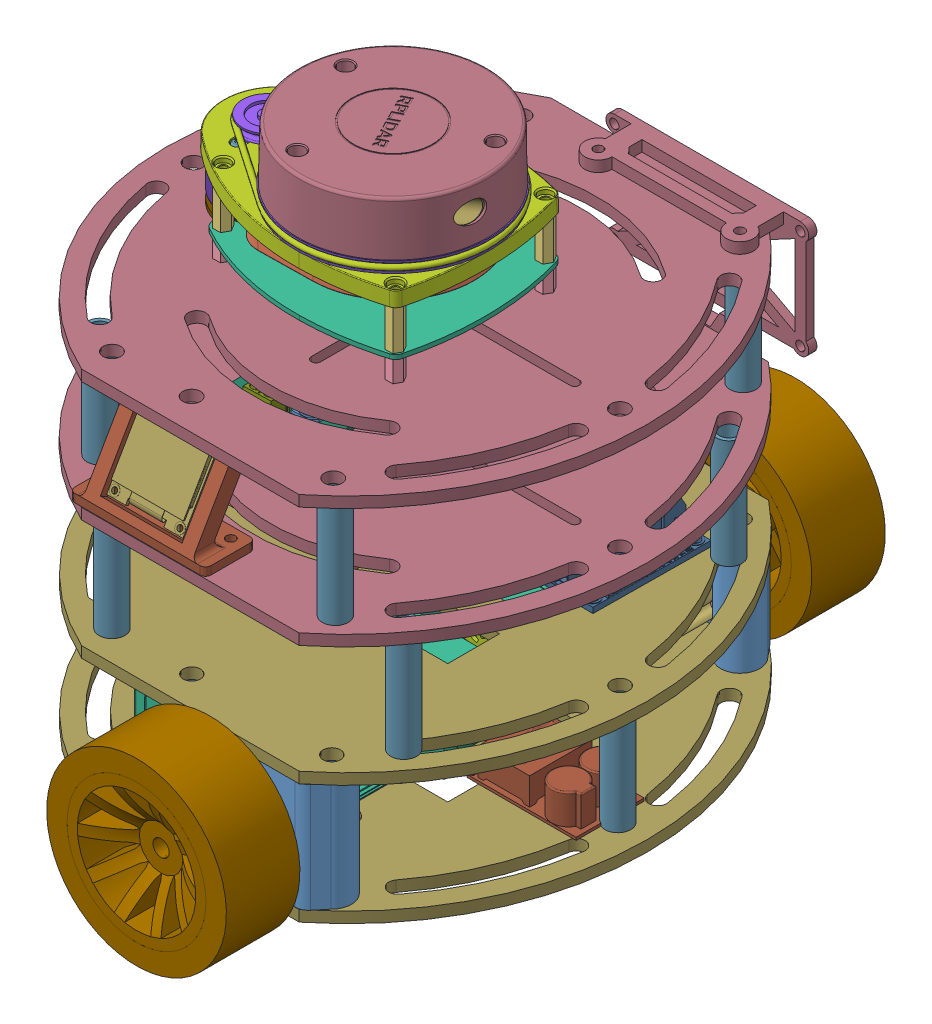
SolidWorks assembly Chelonii, configuration Default. Lengths in mm.
Overall size (176.64 211.73 247).
189 component instances, 85 part files, 48 mates.
Components (placement in the parent):
- Motor_support-1: Motor_support [Default] at (-0.2126 0.5582 64.4885) size (65.8 40 18.4)
- Motor_support-3: Motor_support [Default] at (-0.2126 0.5582 -107.9115) x (-1 0 0) z (0 0 -1) size (65.8 40 18.4)
- faulhaber_2342L012CR-3: faulhaber_2342L012CR [Predeterminado] at (-0.4253 0 -43.216) x (-1 0 0) z (0 0 -1) size (42.85 38.07 98.93)
  - DC GearMotor_Gear_Part1-1: DC GearMotor_Gear_Part1 [Default] at (1.4176 1.4746 34.1956) size (35.2 32 2)
  - DC GearMotor_Gear_Part2-1: DC GearMotor_Gear_Part2 [Default] at (-77.548 2.6324 36.1956) size (35.2 32 18.5)
  - DC GearMotor_Gear_Part3-1: DC GearMotor_Gear_Part3 [Default] at (-1.5149 1.8411 54.6956) size (35.2 31.31 6)
  - DC GearMotor_Gear_Part5-1: DC GearMotor_Gear_Part5 [Default] at (-0.2126 0.5582 50.6956) x (-0.995347 -0.096357 0) z (-0.096357 0.995347 0) size (6 27.8 6)
  - DC GearMotor_Gear_Part4-1: DC GearMotor_Gear_Part4 [Predeterminado] at (-0.2126 0.5582 34.1956) x (-1 0 0) z (0 0 -1) size (41.27 34.92 49.21)
  - DC GearMotor_Gear_Part6-1: DC GearMotor_Gear_Part6 [Predeterminado] at (-0.2126 0.5582 -11.226) x (-0.491683 -0.870774 0) z (0.870774 -0.491683 0) size (27.94 34.61 27.94)
  - DC GearMotor_Gear_Part7-1: DC GearMotor_Gear_Part7 [Predeterminado] at (-0.2126 0.5582 60.6956) x (0.624496 -0.781028 0) z (-0.781028 -0.624496 0) size (15 0.8 15)
- faulhaber_2342L012CR-4: faulhaber_2342L012CR [Predeterminado] at (0 0 -0.2071) size (42.85 38.07 98.93)
  - DC GearMotor_Gear_Part1-1: DC GearMotor_Gear_Part1 [Default] at (1.4176 1.4746 34.1956) size (35.2 32 2)
  - DC GearMotor_Gear_Part2-1: DC GearMotor_Gear_Part2 [Default] at (-77.548 2.6324 36.1956) size (35.2 32 18.5)
  - DC GearMotor_Gear_Part3-1: DC GearMotor_Gear_Part3 [Default] at (-1.5149 1.8411 54.6956) size (35.2 31.31 6)
  - DC GearMotor_Gear_Part5-1: DC GearMotor_Gear_Part5 [Default] at (-0.2126 0.5582 50.6956) x (-0.995347 -0.096357 0) z (-0.096357 0.995347 0) size (6 27.8 6)
  - DC GearMotor_Gear_Part4-1: DC GearMotor_Gear_Part4 [Predeterminado] at (-0.2126 0.5582 34.1956) x (-1 0 0) z (0 0 -1) size (41.27 34.92 49.21)
  - DC GearMotor_Gear_Part6-1: DC GearMotor_Gear_Part6 [Predeterminado] at (-0.2126 0.5582 -11.226) x (-0.491683 -0.870774 0) z (0.870774 -0.491683 0) size (27.94 34.61 27.94)
  - DC GearMotor_Gear_Part7-1: DC GearMotor_Gear_Part7 [Predeterminado] at (-0.2126 0.5582 60.6956) x (0.624496 -0.781028 0) z (-0.781028 -0.624496 0) size (15 0.8 15)
- wheel-1: wheel [Predeterminado] at (-0.2126 0.5582 81.2885) x (0.603366 -0.797465 0) z (0 0 1) size (66 66 35.5)
- wheel-3: wheel [Predeterminado] at (-0.2126 0.5582 -124.7115) x (-0.797465 -0.603366 0) z (0 0 -1) size (66 66 35.5)
- L298N-1: L298N [Default] at (7.2346 24.5582 -61.3002) x (0.009473 0 -0.999955) z (0.999955 0 0.009473) size (43 28.01 43)
- Indicator-1: Indicator [Varsayılan] at (33.5972 -19.4418 -20.8506) x (0 0 1) z (-1 0 0) size (25 12 44)
- Plate_1-8: Plate_1 [Default] at (-15.2126 22.5582 -21.7115) x (0 0 -1) z (1 0 0) size (172.4 4 176.6)
- Plate_1-11: Plate_1 [Default] at (-15.2126 -21.4418 -21.7115) x (0 0 -1) z (1 0 0) size (172.4 4 176.6)
- Plate_2-3: Plate_2 [Default] at (-15.2558 66.5582 -21.6826) x (0 0 -1) z (1 0 0) size (172.4 4 176.6)
- Separator_40mm-1: Separator_40mm [Default] at (-97.8698 0.5582 -42.0829) x (1 0 -0.000077) z (0.000077 0 1) size (9.5 40 9.5)
- Separator_40mm-2: Separator_40mm [Default] at (-98.2169 0.5582 -3.7702) size (9.5 40 9.5)
- LM2596-1: LM2596 [Default] at (-48.6119 68.5582 -24.6591) x (0.03432 0 0.999411) z (-0.999411 0 0.03432) size (66 17.65 36)
  - BASE,  LM2596 Buck Converter 4.0-40 to 1.3-37V-1: BASE,  LM2596 Buck Converter 4.0-40 to 1.3-37V [Default] at origin size (66 1.6 36)
  - DG301-5.0-02, LM2596 Buck Converter 4.0-40 to 1.3-37V-3: DG301-5.0-02, LM2596 Buck Converter 4.0-40 to 1.3-37V [Default] at (29.9 1.6 2.5) x (0 0 -1) z (0 1 0) size (10.6 7.6 14.3)
  - DG301-5.0-02, LM2596 Buck Converter 4.0-40 to 1.3-37V-2: DG301-5.0-02, LM2596 Buck Converter 4.0-40 to 1.3-37V [Default] at (-29.9 1.6 -2.5) x (0 0 1) z (0 1 0) size (10.6 7.6 14.3)
  - 3 DIGIT 7 SEGMENT DISPLAY, LM2596 Buck Converter 4.0-40 to 1.3-37V-1: 3 DIGIT 7 SEGMENT DISPLAY, LM2596 Buck Converter 4.0-40 to 1.3-37V [Default] at (0 8.8 11) size (22.5 13.3 14)
  - Trimpot 3296W, LM2596 Buck Converter 4.0-40 to 1.3-37V-1: Trimpot 3296W, LM2596 Buck Converter 4.0-40 to 1.3-37V [Valor predeterminado] at (5.235 1.6 -15.585) x (-1 0 0) z (0 1 0) size (9.53 4.83 14.15)
  - 220 35V CAPACITOR, LM2596 Buck Converter 4.0-40 to 1.3-37V-1: 220 35V CAPACITOR, LM2596 Buck Converter 4.0-40 to 1.3-37V [Default] at (-19.85 1.6 -7.85) size (8.3 10.5 8.3)
  - 220 35V CAPACITOR, LM2596 Buck Converter 4.0-40 to 1.3-37V-2: 220 35V CAPACITOR, LM2596 Buck Converter 4.0-40 to 1.3-37V [Default] at (18.25 1.6 -6.85) size (8.3 10.5 8.3)
- NUCLEO-F411RE-2: NUCLEO-F411RE [Default] at (-66.072 33.3432 -79.1884) x (-0.999883 0 0.015279) z (0 1 0) size (70 83.97 20.27)
  - NUCLEO-F411RE.STEP-1: NUCLEO-F411RE.STEP [Default] at origin size (70 83.97 20.27)
    - NUCLEO-F411RE_PCB_Varsay_lan.STEP-1: NUCLEO-F411RE_PCB_Varsay_lan.STEP [Default] at origin size (70 82.5 1.5)
    - NUCLEO-F411RE_PCB_HOLEs_Varsay_lan.STEP-1: NUCLEO-F411RE_PCB_HOLEs_Varsay_lan.STEP [Default] at origin size (65.28 79.87 1.57)
    - NUCLEO-F411RE_PCB_TOP_Pads_Varsay_lan.STEP-1: NUCLEO-F411RE_PCB_TOP_Pads_Varsay_lan.STEP [Default] at origin size (59.94 77.1 0.04)
    - NUCLEO-F411RE_PCB_TOP_Solder_Varsay_lan.STEP-1: NUCLEO-F411RE_PCB_TOP_Solder_Varsay_lan.STEP [Default] at origin size (69.8 82.3 0.05)
    - NUCLEO-F411RE_PCB_BOTTOM_Pads_Varsay_lan.STEP-1: NUCLEO-F411RE_PCB_BOTTOM_Pads_Varsay_lan.STEP [Default] at origin size (31.1 70.87 0.04)
    - NUCLEO-F411RE_PCB_BOTTOM_Solder_Varsay_lan.STEP-1: NUCLEO-F411RE_PCB_BOTTOM_Solder_Varsay_lan.STEP [Default] at origin size (69.8 82.3 0.04)
    - NUCLEO-F411RE_PCB_TOP_Overlay_Varsay_lan.STEP-1: NUCLEO-F411RE_PCB_TOP_Overlay_Varsay_lan.STEP [Default] at origin size (68.09 77.67 0)
    - NUCLEO-F411RE_PCB_TOP_Designators_Varsay_lan.STEP-1: NUCLEO-F411RE_PCB_TOP_Designators_Varsay_lan.STEP [Default] at origin size (66.29 79.64 0)
    - NUCLEO-F411RE_PCB_BOTTOM_Overlay_Varsay_lan.STEP-1: NUCLEO-F411RE_PCB_BOTTOM_Overlay_Varsay_lan.STEP [Default] at origin size (40.11 80.77 0)
    - SAMTEC_SSQ-106-01-G-S_for_NUCLEO_Varsay_lan.STEP-1: SAMTEC_SSQ-106-01-G-S_for_NUCLEO_Varsay_lan.STEP [Default] at (-33.02 8.89 0.785) x (0 1 0) z (1 0 0) size (15.75 11.15 2.41)
    - SAMTEC_SSQ-108-01-G-S_for_NUCLEO_Varsay_lan.STEP-1: SAMTEC_SSQ-108-01-G-S_for_NUCLEO_Varsay_lan.STEP [Default] at (-33.02 29.21 0.785) x (0 1 0) z (1 0 0) size (20.83 11.15 2.41)
    - SAMTEC_SSQ-108-01-G-S_for_NUCLEO_Varsay_lan.STEP-2: SAMTEC_SSQ-108-01-G-S_for_NUCLEO_Varsay_lan.STEP [Default] at (15.24 11.43 0.785) x (0 1 0) z (1 0 0) size (20.83 11.15 2.41)
    - SAMTEC_SSQ-110-01-G-S_for_NUCLEO_Varsay_lan.STEP-1: SAMTEC_SSQ-110-01-G-S_for_NUCLEO_Varsay_lan.STEP [Default] at (15.24 35.814 0.785) x (0 1 0) z (1 0 0) size (25.91 11.15 2.41)
    - MOLEX_0678038020_for_NUCLEO.STEP-1: MOLEX_0678038020_for_NUCLEO.STEP [Default] at (3.1721 75.2975 0.785) x (-1 0 0) z (0 1 0) size (9.9 4.95 9)
    - SAMTEC_TSW-119-07-T-D_for_NUCLEO_Varsay_lan.STEP-1: SAMTEC_TSW-119-07-T-D_for_NUCLEO_Varsay_lan.STEP [Default] at (-39.37 25.4 0.785) x (0 -1 0) z (-1 0 0) size (48.26 17.95 5.08)
    - SAMTEC_TSW-119-07-T-D_for_NUCLEO_Varsay_lan.STEP-2: SAMTEC_TSW-119-07-T-D_for_NUCLEO_Varsay_lan.STEP [Default] at (21.59 25.4 0.785) x (0 -1 0) z (-1 0 0) size (48.26 17.95 5.08)
    - SAMTEC_TSW-102-07-T-S_for_NUCLEO_Varsay_lan.STEP-1: SAMTEC_TSW-102-07-T-S_for_NUCLEO_Varsay_lan.STEP [Default] at (-40.64 74.93 0.785) x (0 1 0) z (1 0 0) size (5.08 10.92 2.54)
    - SAMTEC_TSW-102-07-T-S_for_NUCLEO_Varsay_lan.STEP-2: SAMTEC_TSW-102-07-T-S_for_NUCLEO_Varsay_lan.STEP [Default] at (-31.75 59.055 0.785) x (0 -1 0) z (-1 0 0) size (5.08 10.92 2.54)
    - SAMTEC_TSW-102-07-T-S_for_NUCLEO_Varsay_lan.STEP-3: SAMTEC_TSW-102-07-T-S_for_NUCLEO_Varsay_lan.STEP [Default] at (-9.525 77.47 0.785) x (1 0 0) z (0 -1 0) size (5.08 10.92 2.54)
    - SAMTEC_TSW-102-07-T-S_for_NUCLEO_Varsay_lan.STEP-4: SAMTEC_TSW-102-07-T-S_for_NUCLEO_Varsay_lan.STEP [Default] at (-9.525 38.735 0.785) x (1 0 0) z (0 -1 0) size (5.08 10.92 2.54)
    - SAMTEC_TSW-102-07-T-S_for_NUCLEO_Varsay_lan.STEP-5: SAMTEC_TSW-102-07-T-S_for_NUCLEO_Varsay_lan.STEP [Default] at (22.86 74.93 0.785) x (0 -1 0) z (-1 0 0) size (5.08 10.92 2.54)
    - SAMTEC_TSW-103-07-T-S_for_NUCLEO_Varsay_lan.STEP-1: SAMTEC_TSW-103-07-T-S_for_NUCLEO_Varsay_lan.STEP [Default] at (1.905 45.085 0.785) x (1 0 0) z (0 -1 0) size (7.62 10.92 2.54)
    - SAMTEC_TSW-104-07-T-S_for_NUCLEO_Varsay_lan.STEP-1: SAMTEC_TSW-104-07-T-S_for_NUCLEO_Varsay_lan.STEP [Default] at (-21.59 73.66 0.785) x (0 1 0) z (1 0 0) size (10.16 10.92 2.54)
    - SAMTEC_TSW-106-07-T-S_for_NUCLEO_Varsay_lan.STEP-1: SAMTEC_TSW-106-07-T-S_for_NUCLEO_Varsay_lan.STEP [Default] at (-35.56 64.77 0.785) x (0 1 0) z (1 0 0) size (15.24 10.92 2.54)
    - MOLEX_90059-0007.STEP-1: MOLEX_90059-0007.STEP [Default] at (-21.59 76.2 5.75) x (0 1 0) z (1 0 0) size (5.1 4.85 2.54)
    - MOLEX_90059-0007.STEP-2: MOLEX_90059-0007.STEP [Default] at (-21.59 71.12 5.75) x (0 -1 0) z (-1 0 0) size (5.1 4.85 2.54)
    - ST_STM32F411RET6_Varsay_lan.STEP-1: ST_STM32F411RET6_Varsay_lan.STEP [Default] at (-11.4265 21.5935 0.785) x (-1 0 0) z (0 0 -1) size (12 12 1.6)
    - ST_STM32F103CBT6_Varsay_lan.STEP-1: ST_STM32F103CBT6_Varsay_lan.STEP [Default] at (-8.89 64.77 0.785) x (1 0 0) z (0 -1 0) size (9 1.6 9)
    - ESWITCH_TL3301SPF160QGBLK_Varsay_lan.STEP-1: ESWITCH_TL3301SPF160QGBLK_Varsay_lan.STEP [Default] at (-0.635 50.8 0.785) x (0 -1 0) z (-1 0 0) size (6 10.7 10)
    - ESWITCH_TL3301SPF160QGBLU_Varsay_lan.STEP-1: ESWITCH_TL3301SPF160QGBLU_Varsay_lan.STEP [Default] at (-17.145 50.8 0.785) x (0 1 0) z (1 0 0) size (6 10.7 10)
    - ST_STS7PF30L_Varsay_lan.STEP-1: ST_STS7PF30L_Varsay_lan.STEP [Default] at (17.145 60.325 0.785) x (-1 0 0) z (0 1 0) size (4.9 1.75 6)
    - ABRACON_ABL-8.000MHZ-B2_Varsay_lan.STEP-1: ABRACON_ABL-8.000MHZ-B2_Varsay_lan.STEP [Default] at (-18.41 63.4908 0.785) x (0 -1 0) z (-1 0 0) size (11.5 5.57 5)
    - ST_LD1117S50TR_Varsay_lan.STEP-1: ST_LD1117S50TR_Varsay_lan.STEP [Default] at (-14.6685 43.18 0.785) x (0 -1 0) z (-1 0 0) size (6.5 1.9 7)
    - ST_LD39050PU33R_Varsay_lan.STEP-1: ST_LD39050PU33R_Varsay_lan.STEP [Default] at (1.905 40.64 0.785) x (0 1 0) z (1 0 0) size (3 1 3)
    - ST_LD3985M33R_Varsay_lan.STEP-1: ST_LD3985M33R_Varsay_lan.STEP [Default] at (7.62 63.5 0.785) x (1 0 0) z (0 -1 0) size (2.95 1.45 2.8)
    - KEMET_T491B106K025AT_Varsay_lan.STEP-1: KEMET_T491B106K025AT_Varsay_lan.STEP [Default] at (-22.86 41.275 0.785) x (0 -1 0) z (-1 0 0) size (2.8 1.9 3.5)
    - ST_STPS2L30A_Varsay_lan.STEP-1: ST_STPS2L30A_Varsay_lan.STEP [Default] at (-22.86 45.085 0.785) x (0 1 0) z (1 0 0) size (2.58 2.3 5.07)
    - KEMET_T491A106K006AT7280_Varsay_lan.STEP-1: KEMET_T491A106K006AT7280_Varsay_lan.STEP [Default] at (-8.255 43.053 0.785) x (1 0 0) z (0 -1 0) size (1.6 1.6 3.2)
    - ABRACON_ABS25-32.768KHZ-6-T_Varsay_lan.STEP-1: ABRACON_ABS25-32.768KHZ-6-T_Varsay_lan.STEP [Default] at (-23.495 6.35 0.785) x (1 0 0) z (0 -1 0) size (8 2.66 4)
    - LUMEX_SML-LX2835IGC-TR.STEP-1: LUMEX_SML-LX2835IGC-TR.STEP [Default] at (16.51 73.66 0.785) x (1 0 0) z (0 -1 0) size (2.7 1.8 3.5)
    - MOLEX_90059-0007.STEP-3: MOLEX_90059-0007.STEP [Default] at (3.175 45.085 5.75) x (-1 0 0) z (0 1 0) size (5.1 4.85 2.54)
    - ST_BAT60JFILM_Varsay_lan.STEP-1: ST_BAT60JFILM_Varsay_lan.STEP [Default] at (-31.115 71.12 0.785) x (0 -1 0) z (-1 0 0) size (1.28 1.17 2.5)
    - ST_BAT60JFILM_Varsay_lan.STEP-2: ST_BAT60JFILM_Varsay_lan.STEP [Default] at (7.62 69.85 0.785) x (0 -1 0) z (-1 0 0) size (1.28 1.17 2.5)
    - NXP_BC847B,215.STEP-1: NXP_BC847B,215.STEP [Default] at (12.065 64.135 0.785) x (0 -1 0) z (-1 0 0) size (2.9 1.1 2.43)
    - ST_BAT60JFILM_Varsay_lan.STEP-3: ST_BAT60JFILM_Varsay_lan.STEP [Default] at (10.795 59.69 0.785) x (1 0 0) z (0 -1 0) size (1.28 1.17 2.5)
    - YAGEO_CC0805KKX7R7BB225.STEP-1: YAGEO_CC0805KKX7R7BB225.STEP [Default] at (0.127 23.495 0.785) x (0 -1 0) z (-1 0 0) size (1.58 1.29 4.06)
    - YAGEO_RC0603JR-070RL.STEP-1: YAGEO_RC0603JR-070RL.STEP [Default] at (17.145 67.945 0.785) x (1 0 0) z (0 -1 0) size (0.8 0.55 2.16)
    - YAGEO_RC0603JR-070RL.STEP-2: YAGEO_RC0603JR-070RL.STEP [Default] at (15.875 67.945 0.785) x (1 0 0) z (0 -1 0) size (0.8 0.55 2.16)
    - YAGEO_RC0603JR-070RL.STEP-3: YAGEO_RC0603JR-070RL.STEP [Default] at (14.605 67.945 0.785) x (1 0 0) z (0 -1 0) size (0.8 0.55 2.16)
    - YAGEO_RC0603JR-070RL.STEP-4: YAGEO_RC0603JR-070RL.STEP [Default] at (13.335 67.945 0.785) x (1 0 0) z (0 -1 0) size (0.8 0.55 2.16)
    - YAGEO_RC0603JR-070RL.STEP-5: YAGEO_RC0603JR-070RL.STEP [Default] at (12.065 67.945 0.785) x (1 0 0) z (0 -1 0) size (0.8 0.55 2.16)
    - YAGEO_RC0603JR-070RL.STEP-6: YAGEO_RC0603JR-070RL.STEP [Default] at (10.795 67.945 0.785) x (1 0 0) z (0 -1 0) size (0.8 0.55 2.16)
    - YAGEO_RC0603JR-070RL.STEP-7: YAGEO_RC0603JR-070RL.STEP [Default] at (12.7 59.7535 0.785) x (1 0 0) z (0 -1 0) size (0.8 0.55 2.16)
    - YAGEO_RC0603JR-070RL.STEP-8: YAGEO_RC0603JR-070RL.STEP [Default] at (4.445 67.945 0.785) x (1 0 0) z (0 -1 0) size (0.8 0.55 2.16)
    - YAGEO_RC0603JR-070RL.STEP-9: YAGEO_RC0603JR-070RL.STEP [Default] at (3.175 67.945 0.785) x (1 0 0) z (0 -1 0) size (0.8 0.55 2.16)
    - YAGEO_RC0603JR-070RL.STEP-10: YAGEO_RC0603JR-070RL.STEP [Default] at (1.905 67.945 0.785) x (1 0 0) z (0 -1 0) size (0.8 0.55 2.16)
    - YAGEO_RC0603JR-070RL.STEP-11: YAGEO_RC0603JR-070RL.STEP [Default] at (0 67.945 0.785) x (1 0 0) z (0 -1 0) size (0.8 0.55 2.16)
    - YAGEO_RC0603JR-070RL.STEP-12: YAGEO_RC0603JR-070RL.STEP [Default] at (-6.985 73.025 0.785) x (1 0 0) z (0 -1 0) size (0.8 0.55 2.16)
    - YAGEO_RC0603JR-070RL.STEP-13: YAGEO_RC0603JR-070RL.STEP [Default] at (-8.255 73.025 0.785) x (1 0 0) z (0 -1 0) size (0.8 0.55 2.16)
    - YAGEO_RC0603JR-070RL.STEP-14: YAGEO_RC0603JR-070RL.STEP [Default] at (-9.525 73.025 0.785) x (1 0 0) z (0 -1 0) size (0.8 0.55 2.16)
    - YAGEO_RC0603JR-070RL.STEP-15: YAGEO_RC0603JR-070RL.STEP [Default] at (-14.605 73.025 0.785) x (1 0 0) z (0 -1 0) size (0.8 0.55 2.16)
    - YAGEO_RC0603JR-070RL.STEP-16: YAGEO_RC0603JR-070RL.STEP [Default] at (-31.115 73.025 0.785) x (0 -1 0) z (-1 0 0) size (0.8 0.55 2.16)
    - YAGEO_RC0603JR-070RL.STEP-17: YAGEO_RC0603JR-070RL.STEP [Default] at (-31.115 69.215 0.785) x (0 -1 0) z (-1 0 0) size (0.8 0.55 2.16)
    - YAGEO_RC0603JR-070RL.STEP-18: YAGEO_RC0603JR-070RL.STEP [Default] at (-31.115 67.31 0.785) x (0 -1 0) z (-1 0 0) size (0.8 0.55 2.16)
    - YAGEO_RC0603JR-070RL.STEP-19: YAGEO_RC0603JR-070RL.STEP [Default] at (-31.115 65.405 0.785) x (0 -1 0) z (-1 0 0) size (0.8 0.55 2.16)
    - YAGEO_RC0603JR-070RL.STEP-20: YAGEO_RC0603JR-070RL.STEP [Default] at (-31.115 63.5 0.785) x (0 -1 0) z (-1 0 0) size (0.8 0.55 2.16)
    - YAGEO_RC0603JR-070RL.STEP-21: YAGEO_RC0603JR-070RL.STEP [Default] at (-25.4 64.77 0.785) x (0 -1 0) z (-1 0 0) size (0.8 0.55 2.16)
    - YAGEO_RC0603JR-070RL.STEP-22: YAGEO_RC0603JR-070RL.STEP [Default] at (-25.4 63.5 0.785) x (0 -1 0) z (-1 0 0) size (0.8 0.55 2.16)
    - YAGEO_RC0603JR-070RL.STEP-23: YAGEO_RC0603JR-070RL.STEP [Default] at (-25.4 62.23 0.785) x (0 -1 0) z (-1 0 0) size (0.8 0.55 2.16)
    - YAGEO_RC0603JR-070RL.STEP-24: YAGEO_RC0603JR-070RL.STEP [Default] at (-25.4 60.96 0.785) x (0 -1 0) z (-1 0 0) size (0.8 0.55 2.16)
    - YAGEO_RC0603JR-070RL.STEP-25: YAGEO_RC0603JR-070RL.STEP [Default] at (-15.875 11.43 0.785) x (1 0 0) z (0 -1 0) size (0.8 0.55 2.16)
    - YAGEO_RC0603JR-070RL.STEP-26: YAGEO_RC0603JR-070RL.STEP [Default] at (-14.605 11.43 0.785) x (1 0 0) z (0 -1 0) size (0.8 0.55 2.16)
    - YAGEO_RC0603JR-070RL.STEP-27: YAGEO_RC0603JR-070RL.STEP [Default] at (-22.225 18.415 0.785) x (1 0 0) z (0 -1 0) size (0.8 0.55 2.16)
    - YAGEO_RC0603JR-070RL.STEP-28: YAGEO_RC0603JR-070RL.STEP [Default] at (-20.955 32.385 0.785) x (0 -1 0) z (-1 0 0) size (0.8 0.55 2.16)
    - YAGEO_RC0603JR-070RL.STEP-29: YAGEO_RC0603JR-070RL.STEP [Default] at (-8.89 51.435 0.785) x (0 -1 0) z (-1 0 0) size (0.8 0.55 2.16)
    - YAGEO_RC0603JR-070RL.STEP-30: YAGEO_RC0603JR-070RL.STEP [Default] at (-8.89 47.625 0.785) x (0 -1 0) z (-1 0 0) size (0.8 0.55 2.16)
    - YAGEO_RC0603JR-070RL.STEP-31: YAGEO_RC0603JR-070RL.STEP [Default] at (3.81 36.83 0.785) x (0 -1 0) z (-1 0 0) size (0.8 0.55 2.16)
    - YAGEO_RC0603JR-070RL.STEP-32: YAGEO_RC0603JR-070RL.STEP [Default] at (0 63.5 0.785) x (0 -1 0) z (-1 0 0) size (0.8 0.55 2.16)
    - YAGEO_RC0603JR-070RL.STEP-33: YAGEO_RC0603JR-070RL.STEP [Default] at (0 62.23 0.785) x (0 -1 0) z (-1 0 0) size (0.8 0.55 2.16)
    - YAGEO_CC0603KRX7R7BB104.STEP-1: YAGEO_CC0603KRX7R7BB104.STEP [Default] at (-11.43 73.025 0.785) x (1 0 0) z (0 -1 0) size (0.8 0.8 2.16)
    - YAGEO_CC0603KRX7R7BB104.STEP-2: YAGEO_CC0603KRX7R7BB104.STEP [Default] at (-1.905 67.945 0.785) x (1 0 0) z (0 -1 0) size (0.8 0.8 2.16)
    - YAGEO_CC0603KRX7R7BB104.STEP-3: YAGEO_CC0603KRX7R7BB104.STEP [Default] at (5.08 62.865 0.785) x (1 0 0) z (0 -1 0) size (0.8 0.8 2.16)
    - YAGEO_CC0603KRX7R7BB104.STEP-4: YAGEO_CC0603KRX7R7BB104.STEP [Default] at (6.985 59.69 0.785) x (1 0 0) z (0 -1 0) size (0.8 0.8 2.16)
    - YAGEO_CC0603KRX7R7BB104.STEP-5: YAGEO_CC0603KRX7R7BB104.STEP [Default] at (8.89 59.69 0.785) x (1 0 0) z (0 -1 0) size (0.8 0.8 2.16)
    - YAGEO_CC0603KRX7R7BB104.STEP-6: YAGEO_CC0603KRX7R7BB104.STEP [Default] at (-21.59 62.23 0.785) x (1 0 0) z (0 -1 0) size (0.8 0.8 2.16)
    - YAGEO_CC0603KRX7R7BB104.STEP-7: YAGEO_CC0603KRX7R7BB104.STEP [Default] at (-21.59 64.77 0.785) x (1 0 0) z (0 -1 0) size (0.8 0.8 2.16)
    - YAGEO_CC0603KRX7R7BB104.STEP-8: YAGEO_CC0603KRX7R7BB104.STEP [Default] at (-15.24 63.5 0.785) x (1 0 0) z (0 -1 0) size (0.8 0.8 2.16)
    - YAGEO_CC0603KRX7R7BB104.STEP-9: YAGEO_CC0603KRX7R7BB104.STEP [Default] at (-6.35 58.42 0.785) x (0 -1 0) z (-1 0 0) size (0.8 0.8 2.16)
    - YAGEO_CC0603KRX7R7BB104.STEP-10: YAGEO_CC0603KRX7R7BB104.STEP [Default] at (-8.89 53.34 0.785) x (0 -1 0) z (-1 0 0) size (0.8 0.8 2.16)
    - YAGEO_CC0603KRX7R7BB104.STEP-11: YAGEO_CC0603KRX7R7BB104.STEP [Default] at (-8.89 49.53 0.785) x (0 -1 0) z (-1 0 0) size (0.8 0.8 2.16)
    - YAGEO_CC0603KRX7R7BB104.STEP-12: YAGEO_CC0603KRX7R7BB104.STEP [Default] at (-2.54 40.64 0.785) x (1 0 0) z (0 -1 0) size (0.8 0.8 2.16)
    - YAGEO_CC0603KRX7R7BB104.STEP-13: YAGEO_CC0603KRX7R7BB104.STEP [Default] at (-1.27 40.64 0.785) x (1 0 0) z (0 -1 0) size (0.8 0.8 2.16)
    - YAGEO_CC0603KRX7R7BB104.STEP-14: YAGEO_CC0603KRX7R7BB104.STEP [Default] at (5.08 40.64 0.785) x (1 0 0) z (0 -1 0) size (0.8 0.8 2.16)
    - YAGEO_CC0603KRX7R7BB104.STEP-15: YAGEO_CC0603KRX7R7BB104.STEP [Default] at (6.35 40.64 0.785) x (1 0 0) z (0 -1 0) size (0.8 0.8 2.16)
    - YAGEO_CC0603KRX7R7BB104.STEP-16: YAGEO_CC0603KRX7R7BB104.STEP [Default] at (-0.6033 27.94 0.785) x (0 -1 0) z (-1 0 0) size (0.8 0.8 2.16)
    - YAGEO_CC0603KRX7R7BB104.STEP-17: YAGEO_CC0603KRX7R7BB104.STEP [Default] at (-17.145 32.385 0.785) x (1 0 0) z (0 -1 0) size (0.8 0.8 2.16)
    - YAGEO_CC0603KRX7R7BB104.STEP-18: YAGEO_CC0603KRX7R7BB104.STEP [Default] at (-20.32 18.415 0.785) x (1 0 0) z (0 -1 0) size (0.8 0.8 2.16)
    - YAGEO_CC0603KRX7R7BB104.STEP-19: YAGEO_CC0603KRX7R7BB104.STEP [Default] at (-17.145 11.43 0.785) x (1 0 0) z (0 -1 0) size (0.8 0.8 2.16)
    - YAGEO_CC0603KRX7R7BB104.STEP-20: YAGEO_CC0603KRX7R7BB104.STEP [Default] at (0 17.78 0.785) x (0 -1 0) z (-1 0 0) size (0.8 0.8 2.16)
    - YAGEO_CC0603KRX7R7BB104.STEP-21: YAGEO_CC0603KRX7R7BB104.STEP [Default] at (-8.636 12.192 0.785) x (0 -1 0) z (-1 0 0) size (0.8 0.8 2.16)
    - YAGEO_CC0603KRX7R7BB104.STEP-22: YAGEO_CC0603KRX7R7BB104.STEP [Default] at (-19.685 2.794 0.785) x (0 -1 0) z (-1 0 0) size (0.8 0.8 2.16)
    - YAGEO_CC0603KRX7R7BB104.STEP-23: YAGEO_CC0603KRX7R7BB104.STEP [Default] at (-19.685 10.795 0.785) x (0 -1 0) z (-1 0 0) size (0.8 0.8 2.16)
    - LUMEX_SML-LX0603SRW-TR.STEP-1: LUMEX_SML-LX0603SRW-TR.STEP [Default] at (0.635 36.83 0.785) x (1 0 0) z (0 -1 0) size (2.17 0.59 0.81)
    - LUMEX_SML-LX0603GW-TR.STEP-1: LUMEX_SML-LX0603GW-TR.STEP [Default] at (-21.1455 35.5597 0.785) x (1 0 0) z (0 -1 0) size (2.17 0.59 0.81)
- Multistar_3000mAh_4S_Lipo_Battery-1: Multistar_3000mAh_4S_Lipo_Battery [Default] at (-48.2791 -4.4418 2.494) x (0 0 -1) z (0 1 0) size (107 34 26)
- Separator_40mm-4: Separator_40mm [Default] at (55.4594 0.5582 -21.8037) x (1 0 -0.000077) z (0.000077 0 1) size (9.5 40 9.5)
- Separator_40mm-5: Separator_40mm [Default] at (35.1914 44.5582 -82.8593) x (1 0 -0.000077) z (0.000077 0 1) size (9.5 40 9.5)
- Separator_40mm-6: Separator_40mm [Default] at (36.8244 44.5582 38.221) x (1 0 -0.000077) z (0.000077 0 1) size (9.5 40 9.5)
- Separator_40mm-7: Separator_40mm [Default] at (-55.1877 44.5582 -96.7188) x (1 0 -0.000077) z (0.000077 0 1) size (9.5 40 9.5)
- Separator_40mm-8: Separator_40mm [Default] at (-55.1877 44.5582 53.3537) x (1 0 -0.000077) z (0.000077 0 1) size (9.5 40 9.5)
- Plate_2-4: Plate_2 [Default] at (-15.2558 110.5582 -21.6826) x (0 0 -1) z (1 0 0) size (172.4 4 176.6)
- RPlidar-2: RPlidar [Default] at (-111.5946 -607.1341 116.4483) x (-0.999866 0 0.01635) z (-0.01635 0 -0.999866) size (125.66 53.5 112.5)
  - RP-lidar-A1.igs-1: RP-lidar-A1.igs [Default] at origin size (125.66 53.5 112.5)
    - base.igs-1: base.igs [Default] at (-90.5533 748.2923 132.9176) size (107.5 12.7 70.46)
    - head-base.igs-1: head-base.igs [Default] at (-90.5533 751.2923 132.9176) x (0.900173 0 -0.435532) z (0.435532 0 0.900173) size (78.94 21.4 82.8)
    - detector-mount.igs-1: detector-mount.igs [Default] at (-90.4238 754.2923 132.7756) x (-0.437519 0 -0.899209) z (0.899209 0 -0.437519) size (22.2 19.69 24.64)
    - detector.igs-1: detector.igs [Default] at (-93.3269 763.2923 153.0936) x (-0.088661 0.979252 -0.182219) z (-0.899209 0 0.437519) size (14.42 15.28 11.5)
    - laser.igs-1: laser.igs [Default] at (-96.1268 764.2923 107.8262) x (0.382786 0.720375 0.578389) z (-0.833913 0 0.551896) size (6.5 8.25 21.2)
    - laser-mount.igs-1: laser-mount.igs [Default] at (-90.5533 755.2923 132.9176) x (-0.430466 0 -0.902607) z (0.902607 0 -0.430466) size (15.26 18.5 21.53)
    - head.igs-1: head.igs [Default] at (-90.5533 773.1923 132.9176) x (0.435532 0 0.900173) z (0.900173 0 -0.435532) size (84.91 19.5 78.26)
    - Woodscrews_GB_TYPE136 M2X6-N.igs-1: Woodscrews_GB_TYPE136 M2X6-N.igs [Default] at (-64.2029 766.7923 142.3864) x (0 -1 0) z (-0.876166 0 -0.482009) size (7.56 3.91 3.91)
    - Woodscrews_GB_TYPE136 M2X6-N.igs-2: Woodscrews_GB_TYPE136 M2X6-N.igs [Default] at (-81.6242 766.7923 106.3795) x (0 -1 0) z (-0.876166 0 -0.482009) size (7.56 3.91 3.91)
    - Woodscrews_GB_TYPE136 M2X6-N.igs-3: Woodscrews_GB_TYPE136 M2X6-N.igs [Default] at (-115.7581 766.7923 145.1125) x (0 -1 0) z (-0.922446 0 -0.386125) size (7.56 3.91 3.91)
    - Woodscrews_GB_TYPE136 M2X6-N.igs-4: Woodscrews_GB_TYPE136 M2X6-N.igs [Default] at (-45.0533 750.5923 121.9176) x (0 -1 0) z (0.032922 0 0.999458) size (7.56 3.91 3.91)
    - Woodscrews_GB_TYPE136 M2X6-N.igs-5: Woodscrews_GB_TYPE136 M2X6-N.igs [Default] at (-45.0533 750.5923 143.9176) x (0 -1 0) z (0.032922 0 0.999458) size (7.56 3.91 3.91)
    - motherboard.igs-1: motherboard.igs [Default] at (-90.5533 738.2923 132.9176) size (55.5 1 57)
    - connector-1_25-3pin.igs-1: connector-1_25-3pin.igs [Default] at (-57.5533 723.4923 132.5551) x (0 0 1) z (0 -1 0) size (8.9 5.2 3.4)
    - motor.igs-1: motor.igs [Default] at (-45.0533 728.7923 132.9176) x (0 0 1) z (-1 0 0) size (32.79 30.2 32.01)
    - motor-board.igs-1: motor-board.igs [Default] at (-45.0533 725.1923 132.9176) x (0.420142 0 0.907458) z (-0.907458 0 0.420142) size (32 1.6 32)
    - connector-1_25-4pin.igs-1: connector-1_25-4pin.igs [Default] at (-68.3533 736.4423 132.7926) x (0 0 1) z (1 0 0) size (10.15 4.2 4.7)
    - bottom-lid.igs-1: bottom-lid.igs [Default] at (-90.5533 737.2923 132.9176) size (61.38 11.06 61.97)
    - stand_15x2.igs-1: stand_15x2.igs [Default] at (-118.5533 729.2923 160.9176) size (5.77 15 5)
    - stand_15x2.igs-2: stand_15x2.igs [Default] at (-48.5533 729.2923 152.9176) size (5.77 15 5)
    - stand_15x2.igs-3: stand_15x2.igs [Default] at (-48.5533 729.2923 112.9176) size (5.77 15 5)
    - stand_15x2.igs-4: stand_15x2.igs [Default] at (-118.5533 729.2923 104.9176) size (5.77 15 5)
    - stand-8x2.igs-1: stand-8x2.igs [Default] at (-48.5533 727.6923 152.9176) x (1 0 0) z (0 0 -1) size (5.77 8 5)
    - stand-8x2.igs-2: stand-8x2.igs [Default] at (-118.5533 727.6923 160.9176) x (1 0 0) z (0 0 -1) size (5.77 8 5)
    - stand-8x2.igs-3: stand-8x2.igs [Default] at (-118.5533 727.6923 104.9176) x (1 0 0) z (0 0 -1) size (5.77 8 5)
    - stand-8x2.igs-4: stand-8x2.igs [Default] at (-48.5533 727.6923 112.9176) x (1 0 0) z (0 0 -1) size (5.77 8 5)
    - connector-7pin-2_5.igs-1: connector-7pin-2_5.igs [Default] at (-90.5533 727.6923 160.0176) x (0 -1 0) z (1 0 0) size (8.2 5 20)
    - devboard.igs-1: devboard.igs [Default] at (-90.5533 729.2923 132.9176) x (1 0 0) z (0 0 -1) size (85.1 7.64 70)
    - rubber.igs-1: rubber.igs [Default] at (-90.5533 751.4783 132.9176) x (1 0 0) z (0 -1 0) size (103.16 95.72 2.15)
    - wheel.igs-1: wheel.igs [Default] at (-45.0533 749.2923 132.9176) x (-0.124101 0 -0.99227) z (0.99227 0 -0.124101) size (18 5.5 18)
- Separator_40mm-9: Separator_40mm [Default] at (-68.5898 88.5582 44.3302) x (1 0 -0.000077) z (0.000077 0 1) size (9.5 40 9.5)
- Separator_40mm-10: Separator_40mm [Default] at (26.4929 88.5582 -96.7747) x (1 0 -0.000077) z (0.000077 0 1) size (9.5 40 9.5)
- Separator_40mm-11: Separator_40mm [Default] at (25.6865 88.5582 52.1534) x (1 0 -0.000077) z (0.000077 0 1) size (9.5 40 9.5)
- Separator_40mm-12: Separator_40mm [Default] at (-68.1917 88.5582 -87.8881) x (1 0 -0.000077) z (0.000077 0 1) size (9.5 40 9.5)
- Caster_support-1: Caster_support [Default] at (-75.2126 -11.5418 -21.7115) x (0.063829 0 -0.997961) z (0.997961 0 0.063829) size (51.4 19 32.6)
- Caster_0.75in_pololu-2: Caster_0.75in_pololu [Default] at (-75.2126 -11.5418 -21.7115) x (0.412253 0 0.911069) z (0.911069 0 -0.412253) size (22.87 20.95 22.86)
- oled_support-2: oled_support [Default] at (-34.8753 85.4734 52.8036) x (1 0 0) z (0 0.5 0.866025) size (50 35.4 17.43)
- oled-3: oled [Default] at (-34.8753 86.5234 54.6222) x (1 0 0) z (0 0.5 0.866025) size (28 28 11)
- Nextion_support-1: Nextion_support [Default] at (-0.2558 95.2132 -113.3826) x (1 0 0) z (0 0 -1) size (74.52 51.59 22)
Mates (geometry in assembly coordinates):
- Concentric1: concentric aligned: circle of Faulhaber Motor-1/DC GearMotor_Gear_Part3-1; circle of Part1-1
- Coincident1: coincident anti-aligned: plane of Faulhaber Motor-1/DC GearMotor_Gear_Part3-1 through (-1.5149 1.8411 58.4885) normal (0 0 1); plane of Motor_support-1 through (-0.2126 20.5582 58.4885) normal (0 0 -1)
- Concentric2: concentric anti-aligned: circle of Faulhaber Motor-1/DC GearMotor_Gear_Part5-1; circle of Wheel-1
- Concentric4: concentric anti-aligned: circle of Wheel-2; circle of Faulhaber Motor-2/DC GearMotor_Gear_Part5-1
- Concentric5: concentric aligned: circle of Part1-3; circle of Faulhaber Motor-3/DC GearMotor_Gear_Part3-1
- Coincident3: coincident anti-aligned: plane of Motor_support-3 through (-0.2126 20.5582 -101.9115) normal (0 0 1); plane of Faulhaber Motor-3/DC GearMotor_Gear_Part3-1 through (1.0896 1.8411 -101.9115) normal (0 0 -1)
- Parallel1: parallel aligned: plane of Motor_support-1 through (-0.2126 20.5582 64.4885) normal (0 1 0); plane of Motor_support-3 through (-0.2126 20.5582 -107.9115) normal (0 1 0)
- Concentric7: concentric anti-aligned: circle of Part1-1; circle of Part1-3
- Parallel2: parallel aligned: plane of Faulhaber Motor-1/DC GearMotor_Gear_Part4-1 through (-0.2126 17.2269 33.9885) normal (0 1 0); plane of Motor_support-1 through (-0.2126 20.5582 64.4885) normal (0 1 0)
- Parallel3: parallel aligned: plane of Faulhaber Motor-1/DC GearMotor_Gear_Part4-1 through (-0.2126 17.2269 33.9885) normal (0 1 0); plane of Faulhaber Motor-3/DC GearMotor_Gear_Part4-1 through (-0.2126 17.2269 -77.4115) normal (0 1 0)
- Coincident12: coincident anti-aligned: plane of Motor_support-3 through (-0.2126 20.5582 -107.9115) normal (0 1 0); plane of Plate_1-8 through (-15.2126 20.5582 -21.7115) normal (0 -1 0)
- Coincident15: coincident anti-aligned: plane of Faulhaber Motor-1/DC GearMotor_Gear_Part5-1 through (-0.2126 0.5582 78.2885) normal (0 0 1); plane of Wheel-1 through (-0.2126 0.5582 78.2885) normal (0 0 -1)
- Coincident16: coincident anti-aligned: plane of Faulhaber Motor-3/DC GearMotor_Gear_Part5-1 through (-0.2126 0.5582 -121.7115) normal (0 0 -1); plane of Wheel-3 through (-0.2126 0.5582 -121.7115) normal (0 0 1)
- Coincident18: coincident anti-aligned: plane of Motor_support-1 through (-0.2126 -19.4418 64.4885) normal (0 -1 0); plane of Plate_1-11 through (-15.2126 -19.4418 -21.7115) normal (0 1 0)
- Coincident19: coincident anti-aligned: plane of Plate_1-8 through (-15.2126 20.5582 -21.7115) normal (0 -1 0); circle of Separator_40mm-1
- Coincident20: coincident anti-aligned: plane of Plate_1-8 through (-15.2126 20.5582 -21.7115) normal (0 -1 0); plane of Separator_40mm-2 through (-98.2169 20.5582 -3.7702) normal (0 1 0)
- Concentric18: concentric aligned: circle of Motor_support-1; circle of Plate_1-8
- Coincident23: coincident anti-aligned: plane of Indicator-1 through (33.5972 -19.4418 -20.8506) normal (0 -1 0); plane of Plate_1-11 through (-15.2126 -19.4418 -21.7115) normal (0 1 0)
- Parallel9: parallel aligned: plane of Motor_support-3 through (-0.2126 20.5582 -107.9115) normal (0 0 -1); plane of Indicator-1 through (16.4879 -8.4418 -32.3506) normal (0 0 -1)
- Coincident27: coincident anti-aligned: plane of Plate_1-8 through (-15.2126 24.5582 -21.7115) normal (0 1 0); plane of NUCLEO-F411RE-2/NUCLEO-F411RE.STEP-1/SAMTEC_TSW-119-07-T-D_for_NUCLEO_Varsay_lan.STEP-1 through (-24.3797 24.5582 -31.4176) normal (0 -1 0)
- Coincident28: coincident anti-aligned: plane of Plate_1-11 through (-15.2126 -19.4418 -21.7115) normal (0 1 0); plane of Multistar_3000mAh_4S_Lipo_Battery-1 through (-48.2791 -19.4418 2.494) normal (0 -1 0)
- Coincident30: coincident anti-aligned: plane of Plate_1-8 through (-15.2126 20.5582 -21.7115) normal (0 -1 0); plane of Separator_40mm-4 through (55.4594 20.5582 -21.8037) normal (0 1 0)
- Coincident32: coincident anti-aligned: plane of L298N-1 through (7.2346 24.5582 -61.3002) normal (0 -1 0); plane of Plate_1-8 through (-15.2126 24.5582 -21.7115) normal (0 1 0)
- Coincident33: coincident anti-aligned: plane of Plate_1-8 through (-15.2126 24.5582 -21.7115) normal (0 1 0); plane of Separator_40mm-5 through (35.1914 24.5582 -82.8593) normal (0 -1 0)
- Coincident34: coincident anti-aligned: plane of Plate_1-8 through (-15.2126 24.5582 -21.7115) normal (0 1 0); plane of Separator_40mm-6 through (36.8244 24.5582 38.221) normal (0 -1 0)
- Coincident35: coincident anti-aligned: plane of Plate_1-8 through (-15.2126 24.5582 -21.7115) normal (0 1 0); plane of Separator_40mm-8 through (-55.1877 24.5582 53.3537) normal (0 -1 0)
- Coincident36: coincident anti-aligned: plane of Plate_1-8 through (-15.2126 24.5582 -21.7115) normal (0 1 0); plane of Separator_40mm-7 through (-55.1877 24.5582 -96.7188) normal (0 -1 0)
- Coincident40: coincident anti-aligned: plane of Separator_40mm-6 through (36.8244 64.5582 38.221) normal (0 1 0); plane of Plate_2-3 through (-15.2558 64.5582 -21.6826) normal (0 -1 0)
- Concentric26: concentric aligned: circle of Separator_40mm-8; circle of Plate_2-3
- Concentric27: concentric aligned: circle of Separator_40mm-7; circle of Plate_2-3
- Concentric28: concentric aligned: circle of Plate_2-3; circle of Plate_2-4
- Concentric29: concentric aligned: circle of Separator_40mm-7; circle of Plate_2-4
- Tangent1: tangent anti-aligned: plane of Plate_2-4 through (-15.2558 112.5582 -21.6826) normal (0 1 0); face of RPlidar-2/RP-lidar-A1.igs-1/stand-8x2.igs-1
- Coincident42: coincident anti-aligned: plane of Plate_2-3 through (-15.2558 68.5582 -21.6826) normal (0 1 0); plane of Separator_40mm-9 through (-68.5898 68.5582 44.3302) normal (0 -1 0)
- Coincident43: coincident anti-aligned: plane of Plate_2-3 through (-15.2558 68.5582 -21.6826) normal (0 1 0); plane of Separator_40mm-10 through (26.4929 68.5582 -96.7747) normal (0 -1 0)
- Coincident44: coincident anti-aligned: plane of Plate_2-3 through (-15.2558 68.5582 -21.6826) normal (0 1 0); plane of Separator_40mm-11 through (25.6865 68.5582 52.1534) normal (0 -1 0)
- Coincident45: coincident anti-aligned: plane of Plate_2-3 through (-15.2558 68.5582 -21.6826) normal (0 1 0); plane of Separator_40mm-12 through (-68.1917 68.5582 -87.8881) normal (0 -1 0)
- Concentric30: concentric anti-aligned: circle of Plate_1-11; circle of Caster_support-1
- Coincident46: coincident anti-aligned: plane of Plate_1-11 through (-15.2126 -23.4418 -21.7115) normal (0 -1 0); plane of Caster_support-1 through (-75.2126 -23.4418 -21.7115) normal (0 1 0)
- Concentric31: concentric anti-aligned: circle of Caster_support-1; circle of Caster_0.75in_pololu-2
- Coincident47: coincident anti-aligned: plane of Caster_support-1 through (-75.2126 -11.5418 -21.7115) normal (0 -1 0); plane of Caster_0.75in_pololu-2 through (-75.2126 -11.5418 -21.7115) normal (0 1 0)
- Coincident48: coincident anti-aligned: plane of oled_support-2 through (-34.8753 85.9734 53.6696) normal (0 0.5 0.866025); plane of oled-3 through (-34.8753 85.9734 53.6696) normal (0 -0.5 -0.866025)
- Concentric32: concentric anti-aligned: circle of oled_support-2; circle of oled-3
- Concentric33: concentric anti-aligned: circle of oled_support-2; circle of oled-3
- Coincident49: coincident anti-aligned: plane of Plate_2-3 through (-15.2558 68.5582 -21.6826) normal (0 1 0); plane of oled_support-2 through (-34.8753 68.5582 52.8036) normal (0 -1 0)
- Concentric35: concentric aligned: circle of Plate_2-4; circle of Nextion_support-1
- Concentric36: concentric aligned: circle of Plate_2-4; circle of Nextion_support-1
- Coincident50: coincident anti-aligned: plane of Plate_2-4 through (-15.2558 112.5582 -21.6826) normal (0 1 0); plane of Nextion_support-1 through (-0.2558 112.5582 -113.3826) normal (0 -1 0)
